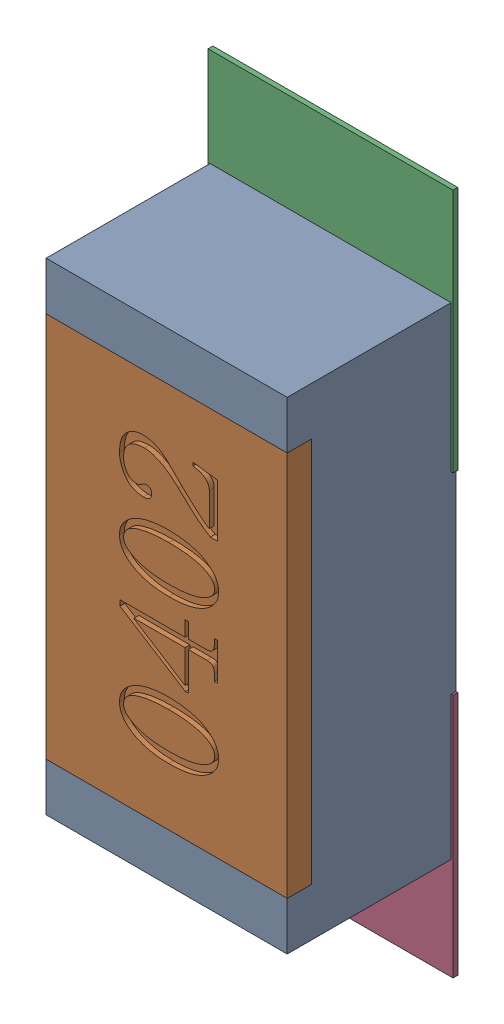
SolidWorks assembly R150, configuration Défaut. Lengths in mm.
Overall size (0.51 1.42 0.35).
5 component instances, 2 part files, 0 mates.
Components (placement in the parent):
- R0402-1: R0402 [Défaut] at (16.2379 -20.9344 0) x (0 1 0) z (0 0 1) size (1 0.5 0.35)
- 6504207776-1: 6504207776 [Défaut] at (16.2377 -20.4844 0) size (0.51 0.51 0.01)
  - Extruded-1: Extruded [Défaut] at origin size (0.51 0.51 0.01)
- 6504207776-2: 6504207776 [Défaut] at (16.2377 -21.3915 0) size (0.51 0.51 0.01)
  - Extruded-1: Extruded [Défaut] at origin size (0.51 0.51 0.01)
